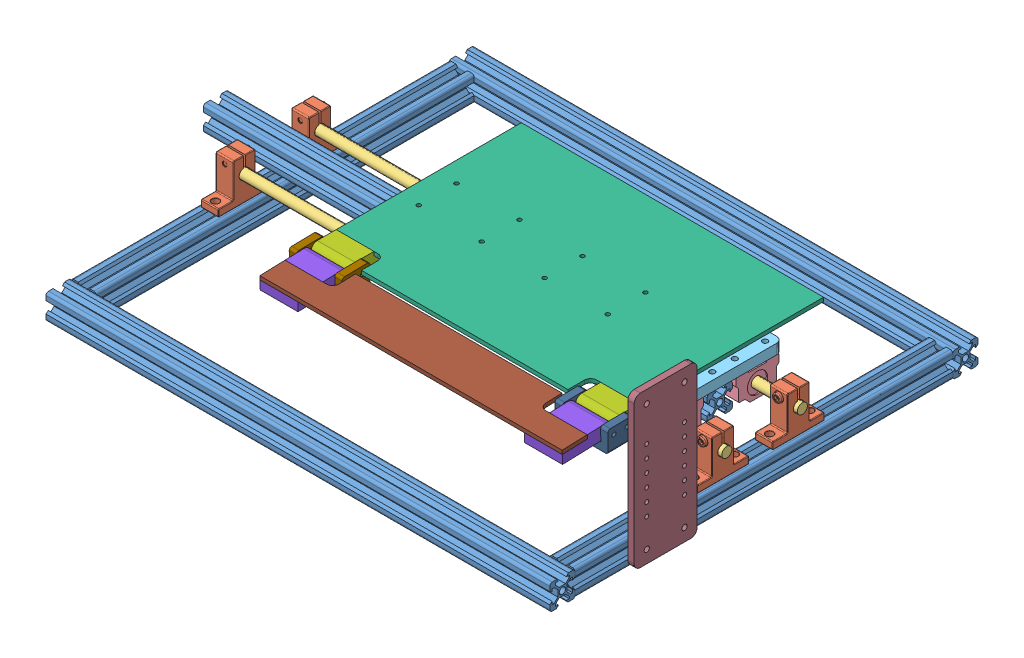
SolidWorks assembly newm, configuration Default. Lengths in mm.
Overall size (440.63 120 340).
27 component instances, 13 part files, 69 mates.
Components (placement in the parent):
- Aluminium Extrusion 2020 V-Slot-1: Aluminium Extrusion 2020 V-Slot [300mm] at (241.1835 10.8701 38.3618) size (20 20 300)
- Aluminium Extrusion 2020 V-Slot-2: Aluminium Extrusion 2020 V-Slot [300mm] at (-138.8165 10.8701 38.3618) size (20 20 300)
- Aluminium Extrusion 2020 V-Slot-3: Aluminium Extrusion 2020 V-Slot [400mm] at (251.1835 10.8701 348.3618) x (0 1 0) z (-1 0 0) size (20 20 400)
- Aluminium Extrusion 2020 V-Slot-4: Aluminium Extrusion 2020 V-Slot [400mm] at (251.1835 10.8701 28.3618) x (0 0 1) z (-1 0 0) size (20 20 400)
- SK8 SC8UU LINEAR RAIL ORIGINAL-1: SK8 SC8UU LINEAR RAIL ORIGINAL [Valor predeterminado] at (248.1335 37.1701 157.7968) x (0 0 1) z (-1 0 0) size (41.13 32.6 13.92)
- SK8 SC8UU LINEAR RAIL ORIGINAL-2: SK8 SC8UU LINEAR RAIL ORIGINAL [Valor predeterminado] at (-145.7665 37.1701 157.7968) x (0 0 -1) z (1 0 0) size (41.13 32.6 13.92)
- SK8 SC8UU LINEAR RAIL ORIGINAL-3: SK8 SC8UU LINEAR RAIL ORIGINAL [Valor predeterminado] at (-145.7665 37.1701 217.7968) x (0 0 -1) z (1 0 0) size (41.13 32.6 13.92)
- SK8 SC8UU LINEAR RAIL ORIGINAL-4: SK8 SC8UU LINEAR RAIL ORIGINAL [Valor predeterminado] at (248.1335 37.1701 217.7968) x (0 0 1) z (-1 0 0) size (41.13 32.6 13.92)
- rod8-3: rod8 [400mm] at (251.1835 40.8801 217.7968) x (0 0.838651 -0.544669) z (0 0.544669 0.838651) size (8 400 8)
- rod8-4: rod8 [400mm] at (-148.8165 40.8801 157.7968) x (0 0.590252 -0.807219) z (0 -0.807219 -0.590252) size (8 400 8)
- SC8UU-1: SC8UU [Default] at (200.5534 40.8801 157.7968) x (0 0 1) z (-1 0 0) size (34 22 30)
- SC8UU-2: SC8UU [Default] at (200.5534 40.8801 217.7968) x (0 0 -1) z (1 0 0) size (34 22 30)
- plate1-1: plate1 [Default] at (200.5534 52.3801 187.7968) x (-1 0 0) z (0 0 -1) size (240 8 100)
- Aluminium Extrusion 2020 V-Slot-5: Aluminium Extrusion 2020 V-Slot [400mm] at (-184.4466 42.3801 187.7968) x (0 0 -1) z (1 0 0) size (20 20 400)
- plate2-1: plate2 [Default] at (95.5534 70.3801 187.7968) x (0 0 1) z (-1 0 0) size (165 3 240)
- hinge1-1: hinge1 [Default] at (-9.4466 63.3801 247.2968) x (0 0 -1) z (1 0 0) size (50 10 30)
- hinge2-1: hinge2 [Default] at (-9.4466 62.6918 292.6159) x (0 -0.034134 0.999417) z (-1 0 0) size (40 10 30)
- hing3-1: hing3 [Default] at (-30.4466 68.2905 272.5461) x (0 0.017069 -0.999854) z (0 -0.999854 -0.017069) size (22 42 17)
- hinge4-1: hinge4 [Default] at (221.5534 68.2905 272.5461) x (0 -0.017069 0.999854) z (0 -0.999854 -0.017069) size (40 42 17)
- hinge1-5: hinge1 [Default] at (200.5534 63.3801 247.2968) x (0 0 -1) z (1 0 0) size (50 10 30)
- hinge2-3: hinge2 [Default] at (200.5534 62.6918 292.6159) x (0 -0.034134 0.999417) z (-1 0 0) size (40 10 30)
- plate3-2: plate3 [Default] at (95.5534 72.6518 293.9566) x (1 0 0) z (0 0.034134 -0.999417) size (240 3 38)
- spacer-1: spacer [Default] at (-8.4466 60.3801 172.7968) x (-0.15223 0 0.988345) z (-0.988345 0 -0.15223) size (8 10 8)
- spacer-2: spacer [Default] at (141.5534 60.3801 172.7968) x (0.641413 0 0.767196) z (-0.767196 0 0.641413) size (8 10 8)
- spacer-3: spacer [Default] at (-8.4466 60.3801 202.7968) x (0.490585 0 0.871393) z (-0.871393 0 0.490585) size (8 10 8)
- spacer-4: spacer [Default] at (141.5534 60.3801 202.7968) x (0.999103 0 0.042355) z (-0.042355 0 0.999103) size (8 10 8)
- plate5-1: plate5 [Default] at (256.1835 60.8701 271.3618) x (0 0 1) z (0 -1 0) size (50 5 120)
Mates (geometry in assembly coordinates):
- Coincident1: coincident aligned: plane of Aluminium Extrusion 2020 V-Slot-2 through (-148.8165 10.8701 338.3618) normal (-1 0 0); plane of Aluminium Extrusion 2020 V-Slot-3 through (-148.8165 10.8701 348.3618) normal (-1 0 0)
- Coincident2: coincident aligned: plane of Aluminium Extrusion 2020 V-Slot-2 through (-138.8165 20.8701 338.3618) normal (0 1 0); plane of Aluminium Extrusion 2020 V-Slot-3 through (-148.8165 20.8701 348.3618) normal (0 1 0)
- Coincident3: coincident anti-aligned: plane of Aluminium Extrusion 2020 V-Slot-2 through (-138.8165 10.8701 338.3618) normal (0 0 1); plane of Aluminium Extrusion 2020 V-Slot-3 through (-148.8165 10.8701 338.3618) normal (0 0 -1)
- Coincident4: coincident anti-aligned: plane of Aluminium Extrusion 2020 V-Slot-1 through (241.1835 10.8701 338.3618) normal (0 0 1); plane of Aluminium Extrusion 2020 V-Slot-3 through (-148.8165 10.8701 338.3618) normal (0 0 -1)
- Coincident5: coincident aligned: plane of Aluminium Extrusion 2020 V-Slot-1 through (241.1835 20.8701 338.3618) normal (0 1 0); plane of Aluminium Extrusion 2020 V-Slot-3 through (-148.8165 20.8701 348.3618) normal (0 1 0)
- Coincident6: coincident aligned: plane of Aluminium Extrusion 2020 V-Slot-1 through (251.1835 10.8701 338.3618) normal (1 0 0); plane of Aluminium Extrusion 2020 V-Slot-3 through (251.1835 10.8701 348.3618) normal (1 0 0)
- Coincident7: coincident aligned: plane of Aluminium Extrusion 2020 V-Slot-1 through (251.1835 10.8701 338.3618) normal (1 0 0); plane of Aluminium Extrusion 2020 V-Slot-4 through (251.1835 10.8701 28.3618) normal (1 0 0)
- Coincident8: coincident aligned: plane of Aluminium Extrusion 2020 V-Slot-1 through (241.1835 20.8701 338.3618) normal (0 1 0); plane of Aluminium Extrusion 2020 V-Slot-4 through (-148.8165 20.8701 28.3618) normal (0 1 0)
- Coincident9: coincident anti-aligned: plane of Aluminium Extrusion 2020 V-Slot-1 through (241.1835 10.8701 38.3618) normal (0 0 -1); plane of Aluminium Extrusion 2020 V-Slot-4 through (-148.8165 10.8701 38.3618) normal (0 0 1)
- Coincident11: coincident anti-aligned: plane of Aluminium Extrusion 2020 V-Slot-1 through (241.1835 20.8701 338.3618) normal (0 1 0); plane of SK8 SC8UU LINEAR RAIL ORIGINAL-4 through (234.2335 20.8701 197.9818) normal (0 -1 0)
- Coincident13: coincident anti-aligned: plane of Aluminium Extrusion 2020 V-Slot-1 through (241.1835 20.8701 338.3618) normal (0 1 0); plane of SK8 SC8UU LINEAR RAIL ORIGINAL-1 through (234.2335 20.8701 137.9818) normal (0 -1 0)
- Coincident15: coincident anti-aligned: plane of Aluminium Extrusion 2020 V-Slot-2 through (-138.8165 20.8701 338.3618) normal (0 1 0); plane of SK8 SC8UU LINEAR RAIL ORIGINAL-3 through (-131.8665 20.8701 237.6118) normal (0 -1 0)
- Coincident17: coincident anti-aligned: plane of Aluminium Extrusion 2020 V-Slot-2 through (-138.8165 20.8701 338.3618) normal (0 1 0); plane of SK8 SC8UU LINEAR RAIL ORIGINAL-2 through (-131.8665 20.8701 177.6118) normal (0 -1 0)
- Width1: width anti-aligned: plane of SK8 SC8UU LINEAR RAIL ORIGINAL-1 through (248.1335 52.4701 165.5711) normal (1 0 0); plane of SK8 SC8UU LINEAR RAIL ORIGINAL-1 through (234.2335 52.4701 165.5711) normal (-1 0 0); plane of Aluminium Extrusion 2020 V-Slot-1 through (231.1835 10.8701 338.3618) normal (-1 0 0); plane of Aluminium Extrusion 2020 V-Slot-1 through (251.1835 10.8701 338.3618) normal (1 0 0)
- Width2: width anti-aligned: plane of SK8 SC8UU LINEAR RAIL ORIGINAL-4 through (248.1335 52.4701 225.5711) normal (1 0 0); plane of SK8 SC8UU LINEAR RAIL ORIGINAL-4 through (234.2335 52.4701 225.5711) normal (-1 0 0); plane of Aluminium Extrusion 2020 V-Slot-1 through (231.1835 10.8701 338.3618) normal (-1 0 0); plane of Aluminium Extrusion 2020 V-Slot-1 through (251.1835 10.8701 338.3618) normal (1 0 0)
- Width3: width anti-aligned: plane of SK8 SC8UU LINEAR RAIL ORIGINAL-3 through (-145.7665 52.4701 210.0225) normal (-1 0 0); plane of SK8 SC8UU LINEAR RAIL ORIGINAL-3 through (-131.8665 52.4701 210.0225) normal (1 0 0); plane of Aluminium Extrusion 2020 V-Slot-2 through (-128.8165 10.8701 338.3618) normal (1 0 0); plane of Aluminium Extrusion 2020 V-Slot-2 through (-148.8165 10.8701 338.3618) normal (-1 0 0)
- Width4: width anti-aligned: plane of SK8 SC8UU LINEAR RAIL ORIGINAL-2 through (-145.7665 52.4701 150.0225) normal (-1 0 0); plane of SK8 SC8UU LINEAR RAIL ORIGINAL-2 through (-131.8665 52.4701 150.0225) normal (1 0 0); plane of Aluminium Extrusion 2020 V-Slot-2 through (-128.8165 10.8701 338.3618) normal (1 0 0); plane of Aluminium Extrusion 2020 V-Slot-2 through (-148.8165 10.8701 338.3618) normal (-1 0 0)
- Concentric2: concentric anti-aligned: cylinder of SK8 SC8UU LINEAR RAIL ORIGINAL-3 through (-115.8665 40.8801 217.7968) axis (-1 0 0) radius 4.01; cylinder of rod8-3 through (-148.8165 40.8801 217.7968) axis (1 0 0) radius 4
- Coincident18: coincident aligned: plane of Aluminium Extrusion 2020 V-Slot-2 through (-148.8165 10.8701 338.3618) normal (-1 0 0); plane of rod8-3 through (-148.8165 40.8801 217.7968) normal (-1 0 0)
- Concentric3: concentric anti-aligned: cylinder of SK8 SC8UU LINEAR RAIL ORIGINAL-1 through (218.2335 40.8801 157.7968) axis (1 0 0) radius 4.01; cylinder of rod8-4 through (251.1835 40.8801 157.7968) axis (-1 0 0) radius 4
- Coincident19: coincident aligned: plane of Aluminium Extrusion 2020 V-Slot-1 through (251.1835 10.8701 338.3618) normal (1 0 0); plane of rod8-4 through (251.1835 40.8801 157.7968) normal (1 0 0)
- Concentric4: concentric aligned: cylinder of SK8 SC8UU LINEAR RAIL ORIGINAL-2 through (-115.8665 40.8801 157.7968) axis (-1 0 0) radius 4.01; cylinder of rod8-4 through (251.1835 40.8801 157.7968) axis (-1 0 0) radius 4
- Concentric5: concentric aligned: cylinder of SK8 SC8UU LINEAR RAIL ORIGINAL-4 through (218.2335 40.8801 217.7968) axis (1 0 0) radius 4.01; cylinder of rod8-3 through (-148.8165 40.8801 217.7968) axis (1 0 0) radius 4
- Distance2: distance = 60 mm: cylinder of rod8-4 through (251.1835 40.8801 157.7968) axis (-1 0 0) radius 4; cylinder of rod8-3 through (-148.8165 40.8801 217.7968) axis (1 0 0) radius 4
- Concentric7: concentric anti-aligned: cylinder of rod8-4 through (251.1835 40.8801 157.7968) axis (-1 0 0) radius 4; cylinder of SC8UU-1 through (186.5534 40.8801 157.7968) axis (1 0 0) radius 4
- Concentric8: concentric anti-aligned: cylinder of rod8-3 through (-148.8165 40.8801 217.7968) axis (1 0 0) radius 4; cylinder of SC8UU-2 through (214.5534 40.8801 217.7968) axis (-1 0 0) radius 4
- Width5: width anti-aligned: plane of plate1-1 through (200.5534 60.3801 237.7968) normal (0 0 1); plane of plate1-1 through (200.5534 60.3801 137.7968) normal (0 0 -1); plane of Aluminium Extrusion 2020 V-Slot-5 through (215.5534 42.3801 177.7968) normal (0 0 -1); plane of Aluminium Extrusion 2020 V-Slot-5 through (215.5534 42.3801 197.7968) normal (0 0 1)
- Concentric9: concentric aligned: cylinder of SC8UU-1 through (191.5534 30.3801 145.7968) axis (0 1 0) radius 1.65; cylinder of plate1-1 through (191.5534 50.3801 145.7968) axis (0 1 0) radius 2.1
- Concentric10: concentric aligned: cylinder of SC8UU-1 through (209.5534 30.3801 145.7968) axis (0 1 0) radius 1.65; cylinder of plate1-1 through (209.5534 50.3801 145.7968) axis (0 1 0) radius 2.1
- Concentric11: concentric aligned: cylinder of SC8UU-2 through (209.5534 30.3801 229.7968) axis (0 1 0) radius 1.65; cylinder of plate1-1 through (209.5534 50.3801 229.7968) axis (0 1 0) radius 2.1
- Concentric12: concentric aligned: cylinder of SC8UU-2 through (191.5534 30.3801 229.7968) axis (0 1 0) radius 1.65; cylinder of plate1-1 through (191.5534 50.3801 229.7968) axis (0 1 0) radius 2.1
- Coincident20: coincident anti-aligned: plane of SC8UU-1 through (185.5534 52.3801 164.7968) normal (0 1 0); plane of plate1-1 through (200.5534 52.3801 187.7968) normal (0 -1 0)
- Coincident21: coincident aligned: plane of plate1-1 through (215.5534 60.3801 187.7968) normal (1 0 0); plane of Aluminium Extrusion 2020 V-Slot-5 through (215.5534 42.3801 187.7968) normal (1 0 0)
- Distance3: distance = 120 mm aligned: plane of SK8 SC8UU LINEAR RAIL ORIGINAL-3 through (-131.8665 21.6201 238.3618) normal (0 0 1); plane of Aluminium Extrusion 2020 V-Slot-3 through (-148.8165 10.8701 358.3618) normal (0 0 1)
- Coincident22: coincident anti-aligned: plane of plate1-1 through (200.5534 52.3801 187.7968) normal (0 -1 0); plane of Aluminium Extrusion 2020 V-Slot-5 through (215.5534 52.3801 187.7968) normal (0 1 0)
- Coincident24: coincident anti-aligned: plane of plate2-1 through (95.5534 70.3801 187.7968) normal (0 -1 0); plane of hinge1-1 through (-9.4466 70.3801 247.2968) normal (0 1 0)
- Coincident25: coincident anti-aligned: plane of plate2-1 through (-24.4466 62.3801 252.2968) normal (0 0 1); plane of hinge1-1 through (5.5534 70.3801 252.2968) normal (0 0 -1)
- Coincident26: coincident aligned: plane of plate2-1 through (-24.4466 73.3801 105.2968) normal (-1 0 0); plane of hinge1-1 through (-24.4466 73.3801 272.2968) normal (-1 0 0)
- Concentric16: concentric anti-aligned: cylinder of hinge1-1 through (-24.4466 68.3801 267.2968) axis (1 0 0) radius 1.75; cylinder of hing3-1 through (11.5534 68.3801 267.2968) axis (-1 0 0) radius 1.75
- Width6: width aligned: plane of hing3-1 through (11.5534 68.2905 272.5461) normal (1 0 0); plane of hing3-1 through (-30.4466 68.2905 272.5461) normal (-1 0 0); plane of hinge1-1 through (5.5534 73.3801 272.2968) normal (1 0 0); plane of hinge1-1 through (-24.4466 73.3801 272.2968) normal (-1 0 0)
- Width7: width anti-aligned: plane of hinge2-1 through (-24.4466 73.3686 272.9689) normal (-1 0 0); plane of hinge2-1 through (5.5534 73.3686 272.9689) normal (1 0 0); plane of hing3-1 through (-30.4466 68.2905 272.5461) normal (-1 0 0); plane of hing3-1 through (11.5534 68.2905 272.5461) normal (1 0 0)
- Concentric17: concentric aligned: cylinder of hinge2-1 through (5.5534 68.2008 277.7953) axis (-1 0 0) radius 1.75; cylinder of hing3-1 through (11.5534 68.2008 277.7953) axis (-1 0 0) radius 1.75
- Coincident33: coincident anti-aligned: plane of plate2-1 through (215.5534 62.3801 252.2968) normal (0 0 1); plane of hinge1-5 through (215.5534 70.3801 252.2968) normal (0 0 -1)
- Coincident34: coincident aligned: plane of plate2-1 through (215.5534 73.3801 105.2968) normal (1 0 0); plane of hinge1-5 through (215.5534 73.3801 272.2968) normal (1 0 0)
- Concentric21: concentric aligned: cylinder of hinge4-1 through (179.5534 68.3801 267.2968) axis (1 0 0) radius 1.6; cylinder of hinge1-5 through (185.5534 68.3801 267.2968) axis (1 0 0) radius 1.75
- Width9: width anti-aligned: plane of hinge4-1 through (221.5534 68.2905 272.5461) normal (1 0 0); plane of hinge4-1 through (179.5534 68.2905 272.5461) normal (-1 0 0); plane of hinge1-5 through (185.5534 73.3801 272.2968) normal (-1 0 0); plane of hinge1-5 through (215.5534 73.3801 272.2968) normal (1 0 0)
- Concentric23: concentric anti-aligned: cylinder of hinge4-1 through (179.5534 68.2008 277.7953) axis (1 0 0) radius 1.6; cylinder of hinge2-3 through (215.5534 68.2008 277.7953) axis (-1 0 0) radius 1.75
- Width10: width aligned: plane of hinge2-3 through (215.5534 73.3686 272.9689) normal (1 0 0); plane of hinge2-3 through (185.5534 73.3686 272.9689) normal (-1 0 0); plane of hinge4-1 through (221.5534 68.2905 272.5461) normal (1 0 0); plane of hinge4-1 through (179.5534 68.2905 272.5461) normal (-1 0 0)
- Coincident39: coincident anti-aligned: plane of hinge2-3 through (200.5534 69.6877 292.8548) normal (0 0.999417 0.034134); plane of plate3-2 through (95.5534 69.6535 293.8542) normal (0 -0.999417 -0.034134)
- Coincident40: coincident anti-aligned: plane of hinge2-3 through (215.5534 69.6877 292.8548) normal (0 -0.034134 0.999417); plane of plate3-2 through (215.5534 72.6859 292.9572) normal (0 0.034134 -0.999417)
- Coincident41: coincident aligned: plane of hinge2-3 through (215.5534 73.3686 272.9689) normal (1 0 0); plane of plate3-2 through (215.5534 69.005 312.8432) normal (1 0 0)
- Coincident42: coincident anti-aligned: plane of plate2-1 through (95.5534 70.3801 187.7968) normal (0 -1 0); plane of hinge1-5 through (200.5534 70.3801 247.2968) normal (0 1 0)
- Coincident43: coincident aligned: plane of plate1-1 through (-24.4466 60.3801 187.7968) normal (-1 0 0); plane of plate2-1 through (-24.4466 73.3801 105.2968) normal (-1 0 0)
- Concentric24: concentric anti-aligned: cylinder of plate1-1 through (-8.4466 50.3801 202.7968) axis (0 1 0) radius 1.6; cylinder of spacer-3 through (-8.4466 70.3801 202.7968) axis (0 -1 0) radius 2.1
- Concentric25: concentric anti-aligned: cylinder of plate1-1 through (-8.4466 50.3801 172.7968) axis (0 1 0) radius 1.6; cylinder of spacer-1 through (-8.4466 70.3801 172.7968) axis (0 -1 0) radius 2.1
- Coincident44: coincident anti-aligned: plane of plate1-1 through (200.5534 60.3801 187.7968) normal (0 1 0); plane of spacer-1 through (-8.4466 60.3801 172.7968) normal (0 -1 0)
- Coincident45: coincident anti-aligned: plane of plate1-1 through (200.5534 60.3801 187.7968) normal (0 1 0); plane of spacer-3 through (-8.4466 60.3801 202.7968) normal (0 -1 0)
- Concentric26: concentric anti-aligned: cylinder of plate1-1 through (141.5534 50.3801 202.7968) axis (0 1 0) radius 1.6; cylinder of spacer-4 through (141.5534 70.3801 202.7968) axis (0 -1 0) radius 2.1
- Coincident46: coincident anti-aligned: plane of plate1-1 through (200.5534 60.3801 187.7968) normal (0 1 0); plane of spacer-4 through (141.5534 60.3801 202.7968) normal (0 -1 0)
- Concentric27: concentric anti-aligned: cylinder of plate1-1 through (141.5534 50.3801 172.7968) axis (0 1 0) radius 1.6; cylinder of spacer-2 through (141.5534 70.3801 172.7968) axis (0 -1 0) radius 2.1
- Coincident47: coincident anti-aligned: plane of plate1-1 through (200.5534 60.3801 187.7968) normal (0 1 0); plane of spacer-2 through (141.5534 60.3801 172.7968) normal (0 -1 0)
- Concentric28: concentric anti-aligned: cylinder of plate2-1 through (141.5534 62.3801 202.7968) axis (0 1 0) radius 1.6; cylinder of spacer-4 through (141.5534 70.3801 202.7968) axis (0 -1 0) radius 2.1
- Concentric29: concentric anti-aligned: cylinder of plate2-1 through (-8.4466 62.3801 172.7968) axis (0 1 0) radius 1.6; cylinder of spacer-1 through (-8.4466 70.3801 172.7968) axis (0 -1 0) radius 2.1
- Coincident48: coincident anti-aligned: plane of plate2-1 through (95.5534 70.3801 187.7968) normal (0 -1 0); plane of spacer-1 through (-8.4466 70.3801 172.7968) normal (0 1 0)
- GearMate1: gear = 3.5 : 3.5 mm: cylinder of hinge1-1 through (-24.4466 68.3801 267.2968) axis (1 0 0) radius 1.75; cylinder of hinge2-1 through (5.5534 68.2008 277.7953) axis (-1 0 0) radius 1.75
- Coincident49: coincident anti-aligned: plane of hinge2-1 through (-9.4466 69.6877 292.8548) normal (0 0.999417 0.034134); plane of plate3-2 through (95.5534 69.6535 293.8542) normal (0 -0.999417 -0.034134)
- Coincident50: coincident anti-aligned: plane of Aluminium Extrusion 2020 V-Slot-3 through (251.1835 10.8701 348.3618) normal (1 0 0); plane of plate5-1 through (251.1835 60.8701 271.3618) normal (-1 0 0)
- Coincident51: coincident aligned: plane of Aluminium Extrusion 2020 V-Slot-1 through (241.1835 0.8701 338.3618) normal (0 -1 0); plane of plate5-1 through (251.1835 0.8701 271.3618) normal (0 -1 0)
- Distance4: distance = 60 mm: plane of plate5-1 through (251.1835 60.8701 296.3618) normal (0 0 1); line of Aluminium Extrusion 2020 V-Slot-3 through (-148.8165 0.8701 356.3618) axis (1 0 0)
